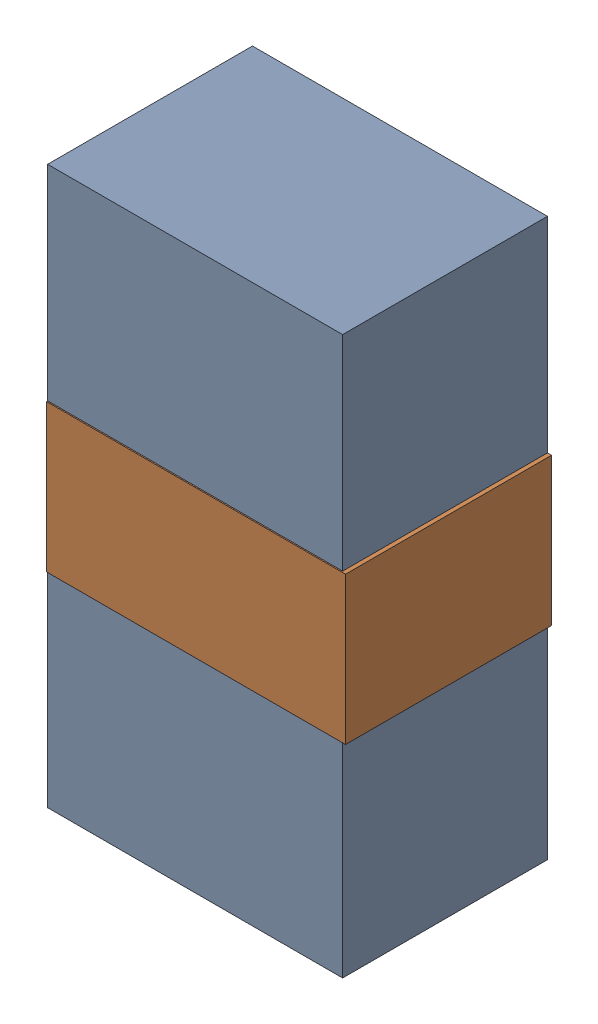
SolidWorks assembly LED2_Motor_6Kanaloa_v2.0.0_Motor, configuration Default. Lengths in mm.
Overall size (1.83 3.4 1.26).
4 component instances, 2 part files, 0 mates.
Components (placement in the parent):
- 334788016-1: 334788016 [Default] at (42.6015 145.288 0) size (1.8 3.4 1.25)
  - Extruded_12-1: Extruded_12 [Default] at origin size (1.8 3.4 1.25)
- 334787760-1: 334787760 [Default] at (42.614 145.288 0) size (1.83 0.9 1.26)
  - Extruded_13-1: Extruded_13 [Default] at origin size (1.83 0.9 1.26)
